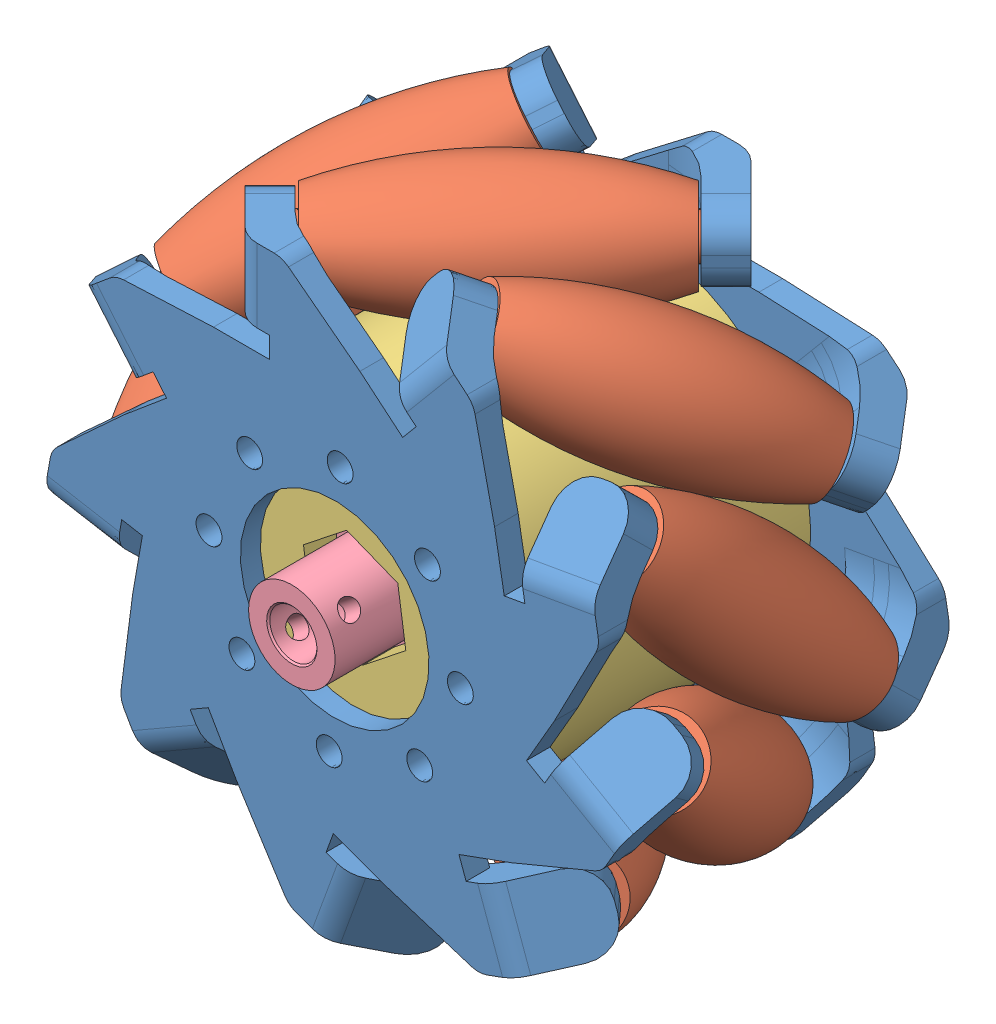
SolidWorks assembly Assem2, configuration Default. Lengths in mm.
Overall size (108.07 108.09 49.8).
13 component instances, 4 part files, 24 mates.
Components (placement in the parent):
- Part1-1: Part1 [Default] at (38.5806 40.6678 49.173) size (76.62 76.81 10.69)
- Part4-1: Part4 [Default] at (23.7658 71.3728 84.7561) x (0.707107 0 -0.707107) z (-0.322728 -0.889771 -0.322728) size (42 16.02 16.02)
- Part1-2: Part1 [Default] at (38.5806 40.6678 90.7095) x (-0.766044 -0.642788 0) z (0 0 -1) size (76.62 76.81 10.69)
- Part4-2: Part4 [Default] at (5.7695 31.4099 84.7561) x (0.122788 0.696364 -0.707107) z (0.923194 0.181319 0.338875) size (42 16.02 16.02)
- Part4-3: Part4 [Default] at (8.2548 55.3039 83.7643) x (0.541675 0.454519 -0.707107) z (0.784684 0.028236 0.619253) size (42 16.02 16.02)
- Part4-4: Part4 [Default] at (42.1996 6.675 84.9682) x (-0.664463 0.241845 -0.707107) z (0.747254 0.227687 -0.624316) size (42 16.02 16.02)
- Part4-5: Part4 [Default] at (63.0037 16.8815 84.7561) x (-0.664463 -0.241845 -0.707107) z (0.747288 -0.223903 -0.625642) size (42 16.02 16.02)
- Part4-6: Part4 [Default] at (19.3967 12.4853 84.7561) x (-0.353553 0.612372 -0.707107) z (0.919239 0.367423 -0.141421) size (42 16.02 16.02)
- Part4-7: Part4 [Default] at (72.5793 38.1453 84.7561) x (-0.353553 -0.612372 -0.707107) z (-0.542742 -0.481382 0.68826) size (42 16.02 16.02)
- Part4-8: Part4 [Default] at (66.2466 60.5894 84.7561) x (0.122788 -0.696364 -0.707107) z (0.923194 -0.181319 0.338875) size (42 16.02 16.02)
- Part4-9: Part4 [Default] at (46.8061 73.8483 84.9682) x (0.541675 -0.454519 -0.707107) z (-0.800356 -0.021745 -0.599131) size (42 16.02 16.02)
- Part2-1: Part2 [Default] at (38.5806 40.6678 52.173) x (0.999048 -0.043619 0) z (-0.043619 -0.999048 0) size (44 36 44)
- 4mm 5mm 6mm Stainless Steel Hex Shaft Coupling-1: 4mm 5mm 6mm Stainless Steel Hex Shaft Coupling [6 mm] at (38.5911 40.5968 78.173) x (-0.145799 0.989314 0) z (0.989314 0.145799 0) size (14.38 18.26 12.53)
Mates (geometry in assembly coordinates):
- Concentric1: concentric anti-aligned: cylinder of Part1-1 through (38.5806 40.6678 52.173) axis (0 0 -1) radius 12; cylinder of Part1-2 through (38.5806 40.6678 87.7095) axis (0 0 1) radius 12
- Concentric2: concentric aligned: cylinder of Part1-2 through (62.2063 16.5913 83.9075) axis (0.664463 0.241845 0.707107) radius 2.9; cylinder of Part4-5 through (63.0037 16.8815 84.7561) axis (0.664463 0.241845 0.707107) radius 2.5
- Distance2: distance = 0.3 mm anti-aligned: plane of Part1-2 through (40.95 41.5302 93.231) normal (-0.664463 -0.241845 -0.707107); plane of Part4-5 through (59.1421 16.7157 84.1988) normal (0.664463 0.241845 0.707107)
- Concentric3: concentric aligned: cylinder of Part1-2 through (41.2029 7.0378 83.9075) axis (0.664463 -0.241845 0.707107) radius 2.9; cylinder of Part4-4 through (42.1996 6.675 84.9682) axis (0.664463 -0.241845 0.707107) radius 2.5
- Coincident3: coincident anti-aligned: plane of Part1-2 through (40.95 39.8054 93.231) normal (-0.664463 0.241845 -0.707107); plane of Part4-4 through (38.338 6.8313 84.4077) normal (0.664463 -0.241845 0.707107)
- Concentric4: concentric aligned: cylinder of Part1-2 through (18.9724 13.2201 83.9075) axis (0.353553 -0.612372 0.707107) radius 2.9; cylinder of Part4-6 through (19.3967 12.4853 84.7561) axis (0.353553 -0.612372 0.707107) radius 2.5
- Distance3: distance = 0.3 mm anti-aligned: plane of Part1-2 through (17.8597 13.8025 82.8469) normal (-0.353553 0.612372 -0.707107); plane of Part4-6 through (16.0379 13.4039 82.9883) normal (0.353553 -0.612372 0.707107)
- Concentric5: concentric aligned: cylinder of Part1-2 through (5.9169 32.2456 83.9075) axis (-0.122788 -0.696364 0.707107) radius 2.9; cylinder of Part4-2 through (5.7695 31.4099 84.7561) axis (-0.122788 -0.696364 0.707107) radius 2.5
- Distance4: distance = 0.3 mm anti-aligned: plane of Part1-2 through (5.4388 33.4069 82.8469) normal (0.122788 0.696364 -0.707107); plane of Part4-2 through (3.8299 33.0457 81.7876) normal (-0.122788 -0.696364 0.707107)
- Concentric6: concentric aligned: cylinder of Part4-1 through (23.7658 71.3728 84.7561) axis (-0.707107 0 0.707107) radius 2.5; cylinder of Part1-2 through (24.6143 71.3728 83.9075) axis (-0.707107 0 0.707107) radius 2.9
- Distance5: distance = 0.3 mm anti-aligned: plane of Part1-2 through (25.675 72.0453 82.8469) normal (0.707107 0 -0.707107); plane of Part4-1 through (26.6939 73.5972 83.4416) normal (-0.707107 0 0.707107)
- Concentric7: concentric aligned: cylinder of Part1-2 through (47.6186 73.1665 83.9075) axis (-0.541675 0.454519 0.707107) radius 2.9; cylinder of Part4-9 through (46.8061 73.8483 84.9682) axis (-0.541675 0.454519 0.707107) radius 2.5
- Coincident7: coincident anti-aligned: plane of Part1-2 through (48.8634 72.9999 82.8469) normal (0.541675 -0.454519 -0.707107); plane of Part4-9 through (50.432 72.5391 84.3447) normal (-0.541675 0.454519 0.707107)
- Concentric8: concentric aligned: cylinder of Part1-2 through (66.3939 59.7538 83.9075) axis (-0.122788 0.696364 0.707107) radius 2.9; cylinder of Part4-8 through (66.2466 60.5894 84.7561) axis (-0.122788 0.696364 0.707107) radius 2.5
- Distance6: distance = 0.3 mm anti-aligned: plane of Part1-2 through (65.9158 58.5924 82.8469) normal (0.122788 -0.696364 -0.707107); plane of Part4-8 through (64.3069 58.9536 81.7876) normal (-0.122788 0.696364 0.707107)
- Concentric9: concentric aligned: cylinder of Part1-2 through (72.155 37.4104 83.9075) axis (0.353553 0.612372 0.707107) radius 2.9; cylinder of Part4-7 through (72.5793 38.1453 84.7561) axis (0.353553 0.612372 0.707107) radius 2.5
- Distance7: distance = 0.3 mm anti-aligned: plane of Part1-2 through (39.8413 42.8515 93.231) normal (-0.353553 -0.612372 -0.707107); plane of Part4-7 through (72.8755 37.5116 80.9141) normal (0.353553 0.612372 0.707107)
- Concentric10: concentric anti-aligned: cylinder of Part1-1 through (58.1888 13.2201 55.975) axis (-0.353553 -0.612372 -0.707107) radius 2.9; cylinder of Part4-7 through (72.5793 38.1453 84.7561) axis (0.353553 0.612372 0.707107) radius 2.5
- Coincident10: coincident anti-aligned: plane of Part1-1 through (38.5806 40.6678 52.173) normal (0 0 1); plane of Part2-1 through (38.5806 40.6678 52.173) normal (0 0 -1)
- Concentric11: concentric aligned: cylinder of Part1-2 through (50.377 51.4772 87.7095) axis (0 0 1) radius 1.65; cylinder of Part2-1 through (50.377 51.4772 52.173) axis (0 0 1) radius 1.65
- Concentric12: concentric aligned: cylinder of Part1-2 through (22.5958 41.3657 87.7095) axis (0 0 1) radius 1.65; cylinder of Part2-1 through (22.5958 41.3657 52.173) axis (0 0 1) radius 1.65
- Coincident12: coincident anti-aligned: plane of Part2-1 through (33.0935 36.3213 78.173) normal (0.368392 0.929671 0); plane of 4mm 5mm 6mm Stainless Steel Hex Shaft Coupling-1 through (33.1602 36.2949 84.173) normal (-0.368392 -0.929671 0)
- Coincident13: coincident anti-aligned: plane of Part2-1 through (39.6012 33.7426 78.173) normal (-0.620923 0.783872 0); plane of 4mm 5mm 6mm Stainless Steel Hex Shaft Coupling-1 through (39.6012 33.7426 84.173) normal (0.620923 -0.783872 0)
- Coincident14: coincident anti-aligned: plane of Part2-1 through (38.5806 40.6678 78.173) normal (0 0 1); plane of 4mm 5mm 6mm Stainless Steel Hex Shaft Coupling-1 through (38.5911 40.5968 78.173) normal (0 0 -1)
